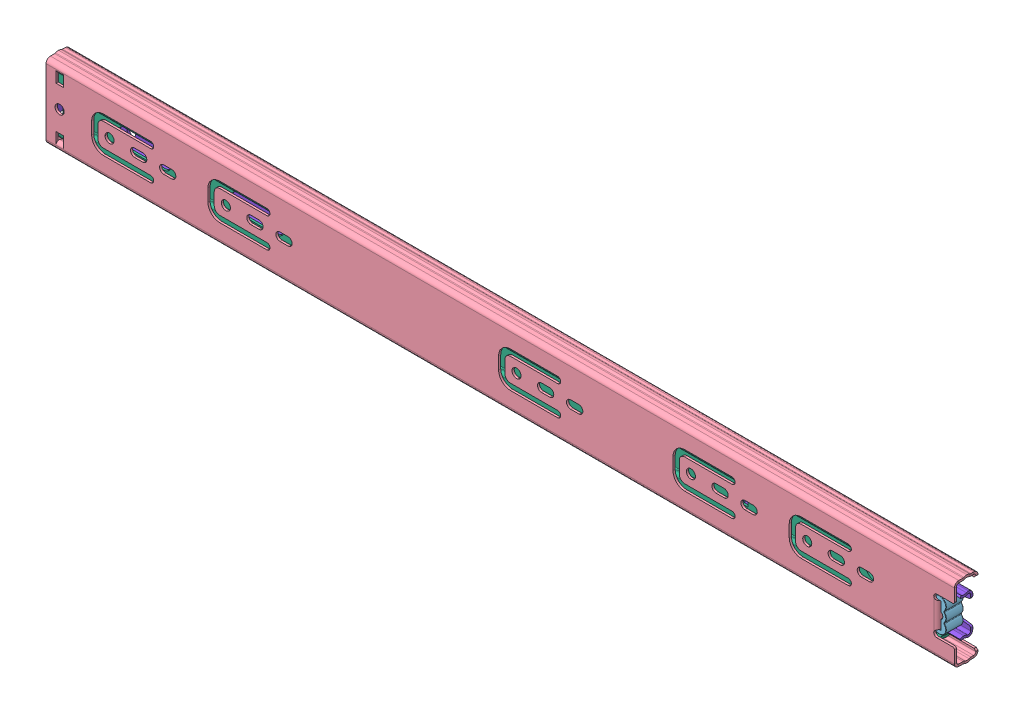
SolidWorks assembly Telescopic Slides.STEP, configuration Default. Lengths in mm.
Overall size (500 42 13.01).
57 component instances, 10 part files, 0 mates.
Components (placement in the parent):
- Ball Bearing Slide_500.STEP-1: Ball Bearing Slide_500.STEP [Default] at (26.6107 0 -7.4) x (1 0 0) z (0 1 0) size (200 6.92 30.59)
  - Bearing Slide_500.STEP-1: Bearing Slide_500.STEP [Default] at origin size (200 6.92 27.5)
  - Ball.STEP-1: Ball.STEP [Default] at (-95 1.2158 -12.9657) x (0 -0.145494 -0.989359) z (-0.970445 0.238753 -0.035111) size (4 4 4)
  - Ball.STEP-2: Ball.STEP [Default] at (-82 1.2158 -12.9657) x (0 -0.145494 -0.989359) z (-0.970445 0.238753 -0.035111) size (4 4 4)
  - Ball.STEP-3: Ball.STEP [Default] at (-95 1.2158 12.9657) x (0 -0.145494 0.989359) z (0.970445 -0.238753 -0.035111) size (4 4 4)
  - Ball.STEP-4: Ball.STEP [Default] at (-82 1.2158 12.9657) x (0 -0.145494 0.989359) z (0.970445 -0.238753 -0.035111) size (4 4 4)
  - Ball.STEP-5: Ball.STEP [Default] at (-70 1.2158 12.9657) x (0 -0.145494 0.989359) z (0.970445 -0.238753 -0.035111) size (4 4 4)
  - Ball.STEP-6: Ball.STEP [Default] at (-45 1.2158 12.9657) x (0 -0.145494 0.989359) z (0.970445 -0.238753 -0.035111) size (4 4 4)
  - Ball.STEP-7: Ball.STEP [Default] at (-20 1.2158 12.9657) x (0 -0.145494 0.989359) z (0.970445 -0.238753 -0.035111) size (4 4 4)
  - Ball.STEP-8: Ball.STEP [Default] at (5 1.2158 12.9657) x (0 -0.145494 0.989359) z (0.970445 -0.238753 -0.035111) size (4 4 4)
  - Ball.STEP-9: Ball.STEP [Default] at (30 1.2158 12.9657) x (0 -0.145494 0.989359) z (0.970445 -0.238753 -0.035111) size (4 4 4)
  - Ball.STEP-10: Ball.STEP [Default] at (55 1.2158 12.9657) x (0 -0.145494 0.989359) z (0.970445 -0.238753 -0.035111) size (4 4 4)
  - Ball.STEP-11: Ball.STEP [Default] at (80 1.2158 12.9657) x (0 -0.145494 0.989359) z (0.970445 -0.238753 -0.035111) size (4 4 4)
  - Ball.STEP-12: Ball.STEP [Default] at (-57 1.2158 12.9657) x (0 -0.145494 0.989359) z (0.970445 -0.238753 -0.035111) size (4 4 4)
  - Ball.STEP-13: Ball.STEP [Default] at (-32 1.2158 12.9657) x (0 -0.145494 0.989359) z (0.970445 -0.238753 -0.035111) size (4 4 4)
  - Ball.STEP-14: Ball.STEP [Default] at (-7 1.2158 12.9657) x (0 -0.145494 0.989359) z (0.970445 -0.238753 -0.035111) size (4 4 4)
  - Ball.STEP-15: Ball.STEP [Default] at (18 1.2158 12.9657) x (0 -0.145494 0.989359) z (0.970445 -0.238753 -0.035111) size (4 4 4)
  - Ball.STEP-16: Ball.STEP [Default] at (43 1.2158 12.9657) x (0 -0.145494 0.989359) z (0.970445 -0.238753 -0.035111) size (4 4 4)
  - Ball.STEP-17: Ball.STEP [Default] at (68 1.2158 12.9657) x (0 -0.145494 0.989359) z (0.970445 -0.238753 -0.035111) size (4 4 4)
  - Ball.STEP-18: Ball.STEP [Default] at (93 1.2158 12.9657) x (0 -0.145494 0.989359) z (0.970445 -0.238753 -0.035111) size (4 4 4)
  - Ball.STEP-19: Ball.STEP [Default] at (-70 1.2158 -12.9657) x (0 -0.145494 -0.989359) z (-0.970445 0.238753 -0.035111) size (4 4 4)
  - Ball.STEP-20: Ball.STEP [Default] at (-45 1.2158 -12.9657) x (0 -0.145494 -0.989359) z (-0.970445 0.238753 -0.035111) size (4 4 4)
  - Ball.STEP-21: Ball.STEP [Default] at (-20 1.2158 -12.9657) x (0 -0.145494 -0.989359) z (-0.970445 0.238753 -0.035111) size (4 4 4)
  - Ball.STEP-22: Ball.STEP [Default] at (5 1.2158 -12.9657) x (0 -0.145494 -0.989359) z (-0.970445 0.238753 -0.035111) size (4 4 4)
  - Ball.STEP-23: Ball.STEP [Default] at (30 1.2158 -12.9657) x (0 -0.145494 -0.989359) z (-0.970445 0.238753 -0.035111) size (4 4 4)
  - Ball.STEP-24: Ball.STEP [Default] at (55 1.2158 -12.9657) x (0 -0.145494 -0.989359) z (-0.970445 0.238753 -0.035111) size (4 4 4)
  - Ball.STEP-25: Ball.STEP [Default] at (80 1.2158 -12.9657) x (0 -0.145494 -0.989359) z (-0.970445 0.238753 -0.035111) size (4 4 4)
  - Ball.STEP-26: Ball.STEP [Default] at (-57 1.2158 -12.9657) x (0 -0.145494 -0.989359) z (-0.970445 0.238753 -0.035111) size (4 4 4)
  - Ball.STEP-27: Ball.STEP [Default] at (-32 1.2158 -12.9657) x (0 -0.145494 -0.989359) z (-0.970445 0.238753 -0.035111) size (4 4 4)
  - Ball.STEP-28: Ball.STEP [Default] at (-7 1.2158 -12.9657) x (0 -0.145494 -0.989359) z (-0.970445 0.238753 -0.035111) size (4 4 4)
  - Ball.STEP-29: Ball.STEP [Default] at (18 1.2158 -12.9657) x (0 -0.145494 -0.989359) z (-0.970445 0.238753 -0.035111) size (4 4 4)
  - Ball.STEP-30: Ball.STEP [Default] at (43 1.2158 -12.9657) x (0 -0.145494 -0.989359) z (-0.970445 0.238753 -0.035111) size (4 4 4)
  - Ball.STEP-31: Ball.STEP [Default] at (68 1.2158 -12.9657) x (0 -0.145494 -0.989359) z (-0.970445 0.238753 -0.035111) size (4 4 4)
  - Ball.STEP-32: Ball.STEP [Default] at (93 1.2158 -12.9657) x (0 -0.145494 -0.989359) z (-0.970445 0.238753 -0.035111) size (4 4 4)
- Plastic Ball Bearing Stick_500.STEP-1: Plastic Ball Bearing Stick_500.STEP [Default] at (101.7107 17.8 -6.7) x (0 -1 0) z (1 0 0) size (4 5.58 250)
  - Plastic Bearing Stick_500.STEP-1: Plastic Bearing Stick_500.STEP [Default] at origin size (2 5 250)
  - Ball.STEP-1: Ball.STEP [Default] at (0 0 115) x (1 0 0) z (0 0.579439 -0.815016) size (4 4 4)
  - Ball.STEP-2: Ball.STEP [Default] at (0 0 69) x (1 0 0) z (0 0.579439 -0.815016) size (4 4 4)
  - Ball.STEP-3: Ball.STEP [Default] at (0 0 23) x (1 0 0) z (0 0.579439 -0.815016) size (4 4 4)
  - Ball.STEP-4: Ball.STEP [Default] at (0 0 -23) x (1 0 0) z (0 0.579439 -0.815016) size (4 4 4)
  - Ball.STEP-5: Ball.STEP [Default] at (0 0 -69) x (1 0 0) z (0 0.579439 -0.815016) size (4 4 4)
  - Ball.STEP-6: Ball.STEP [Default] at (0 0 -115) x (1 0 0) z (0 0.579439 -0.815016) size (4 4 4)
- Plastic Ball Bearing Stick_500-1.STEP-1: Plastic Ball Bearing Stick_500-1.STEP [Default] at (101.7107 -17.8 -6.7) x (0 1 0) z (-1 0 0) size (4 5.58 250)
  - Plastic Bearing Stick_500.STEP-1: Plastic Bearing Stick_500.STEP [Default] at origin size (2 5 250)
  - Ball.STEP-1: Ball.STEP [Default] at (0 0 115) x (1 0 0) z (0 0.579439 -0.815016) size (4 4 4)
  - Ball.STEP-2: Ball.STEP [Default] at (0 0 69) x (1 0 0) z (0 0.579439 -0.815016) size (4 4 4)
  - Ball.STEP-3: Ball.STEP [Default] at (0 0 23) x (1 0 0) z (0 0.579439 -0.815016) size (4 4 4)
  - Ball.STEP-4: Ball.STEP [Default] at (0 0 -23) x (1 0 0) z (0 0.579439 -0.815016) size (4 4 4)
  - Ball.STEP-5: Ball.STEP [Default] at (0 0 -69) x (1 0 0) z (0 0.579439 -0.815016) size (4 4 4)
  - Ball.STEP-6: Ball.STEP [Default] at (0 0 -115) x (1 0 0) z (0 0.579439 -0.815016) size (4 4 4)
- Big Slide_500.STEP-1: Big Slide_500.STEP [Default] at origin size (500 42 13.01)
- Rubber Back Stopper.STEP-1: Rubber Back Stopper.STEP [Default] at (240.4607 0 -5.95) x (1 0 0) z (0 -1 0) size (7.5 9.5 18.5)
- Middle Slide_500.STEP-1: Middle Slide_500.STEP [Default] at (-4.2893 0 -4.7) x (0 0 -1) z (1 0 0) size (10 32.69 482)
- Plastic Front Stopper.STEP-1: Plastic Front Stopper.STEP [Default] at (-237.2893 0 -5.9) x (1 0 0) z (0 1 0) size (18.05 10.13 31.18)
- Small Slide_500.STEP-1: Small Slide_500.STEP [Default] at (-0.3782 0 -10.8) size (496.76 22 9.49)
- Plastic Lock.STEP-1: Plastic Lock.STEP [Default] at (73.6218 0 -10.8) x (0.999989 0.004777 0) z (0.004777 -0.999989 0) size (63 2.7 18.97)
- Rivet.STEP-1: Rivet.STEP [Default] at (73.6218 0 -10.3) x (-0.601797 0.798649 0) z (-0.798649 -0.601797 0) size (7 3.5 7)
